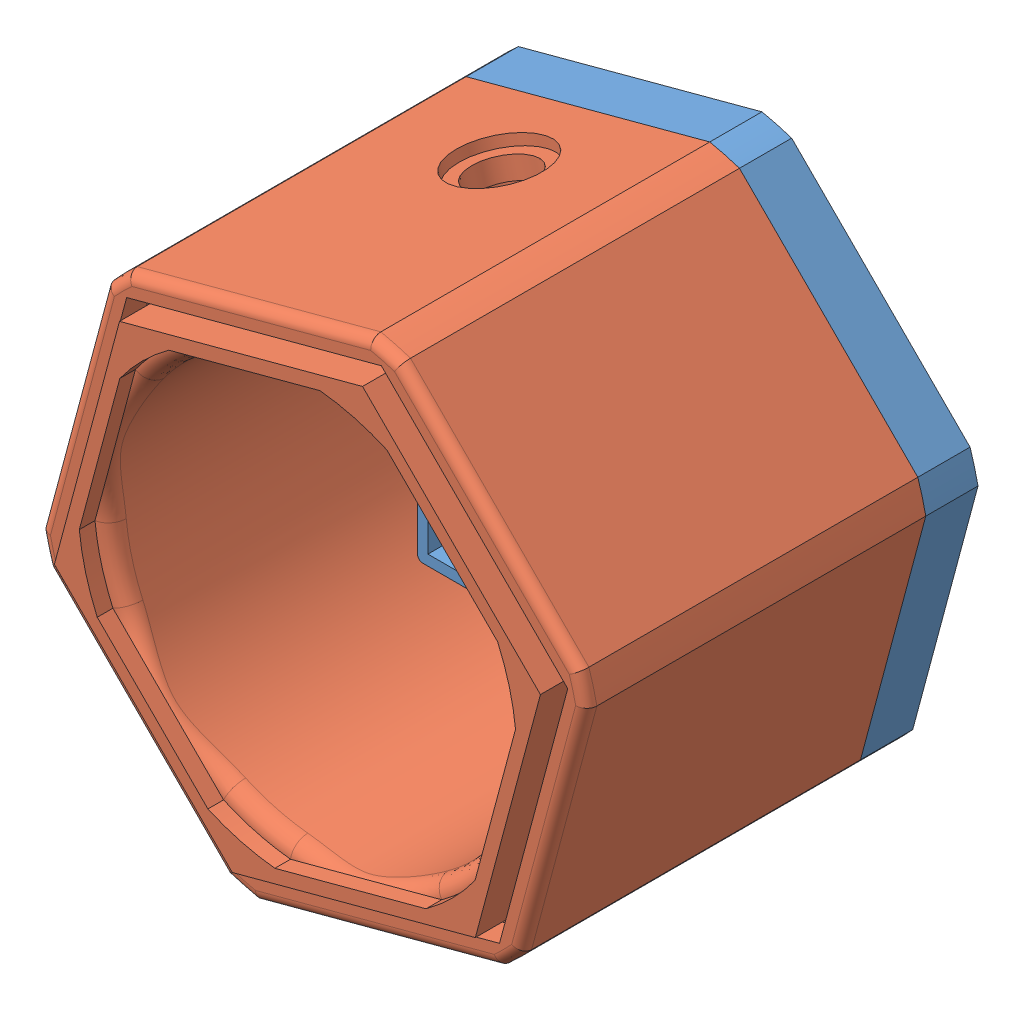
SolidWorks assembly Подставка умного светильника_HEX, configuration По умолчанию. Lengths in mm.
Overall size (104.95 104.95 78).
2 component instances, 2 part files, 4 mates.
Components (placement in the parent):
- Нижняя часть подставки-1: Нижняя часть подставки [По умолчанию] at origin size (104.72 104.72 45)
- Копия Копия Цилиндр светильника^Подставка умного светильника_HEX-1: Копия Копия Цилиндр светильника^Подставка умного светильника_HEX [По умолчанию] at origin size (104.95 104.95 68) (virtual)
Mates (geometry in assembly coordinates):
- На месте1: in place: plane of ? through (0 0 0) normal (0 0 1); plane of ? through (0 0 0) normal (0 0 1); moOrthogonalPlaneRef_w of ? through (0 0 0) normal (0 0 1); plane of ? through (0 0 0) normal (0 1 0); plane of ? through (0 0 0) normal (0 0 1); plane of ? through (0 0 0) normal (1 0 0); plane of ? through (0 0 0) normal (0 0 1); unknown of ?
- Совпадение1: coincident aligned: plane of Нижняя часть подставки-1; plane of Копия Копия Цилиндр светильника^Подставка умного светильника_HEX-1
- Совпадение2: coincident aligned: moOrthogonalPlaneRef_w of Нижняя часть подставки-1 through (0 0 0) normal (0 1 0); plane of Копия Копия Цилиндр светильника^Подставка умного светильника_HEX-1 through (0 0 0) normal (0 1 0)
- Совпадение3: coincident anti-aligned: moOrthogonalPlaneRef_w of Нижняя часть подставки-1 through (0 0 0) normal (-1 0 0); plane of Копия Копия Цилиндр светильника^Подставка умного светильника_HEX-1 through (0 0 0) normal (1 0 0)
